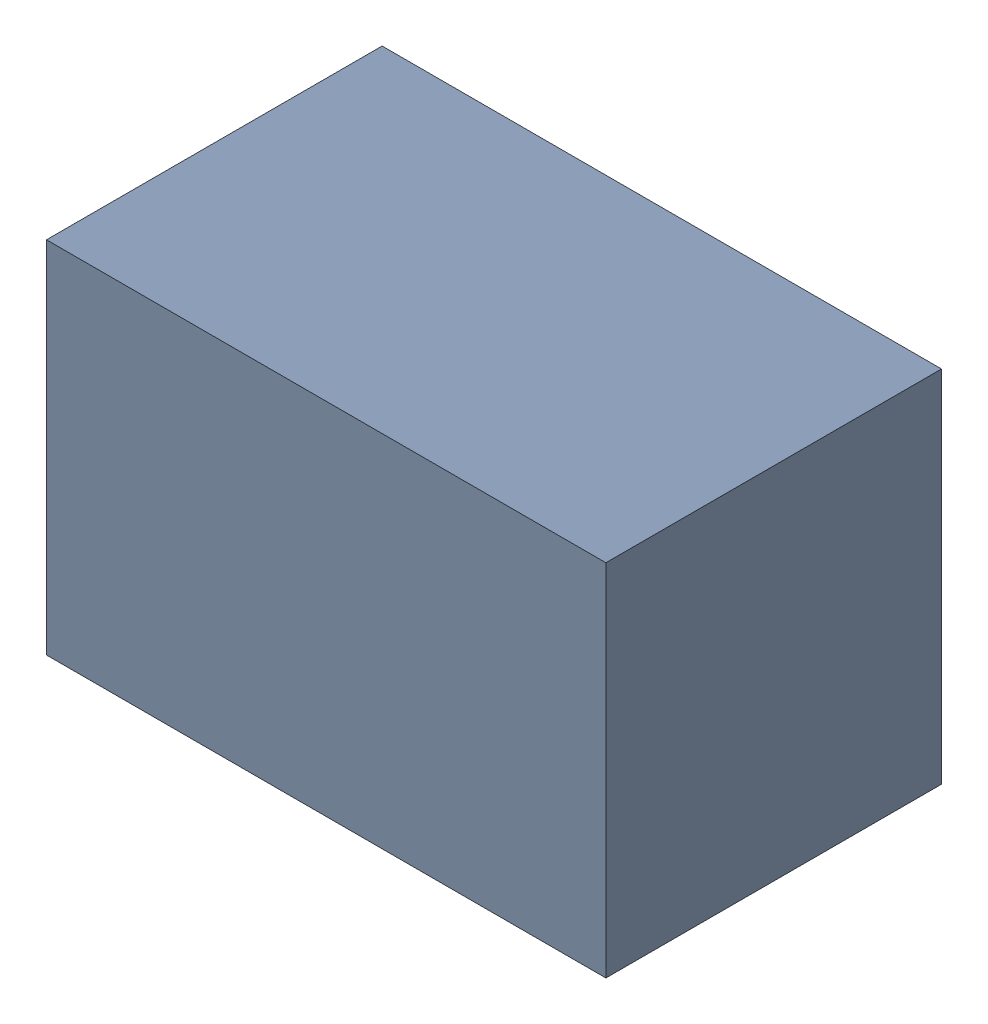
SolidWorks assembly C53, configuration Default. Lengths in mm.
Overall size (2.1 1.35 1.26).
2 component instances, 1 part files, 0 mates.
Components (placement in the parent):
- 407985824-1: 407985824 [Default] at (40.64 20.2946 0.0127) size (2.1 1.35 1.26)
  - Extruded_2-1: Extruded_2 [Default] at origin size (2.1 1.35 1.26)
